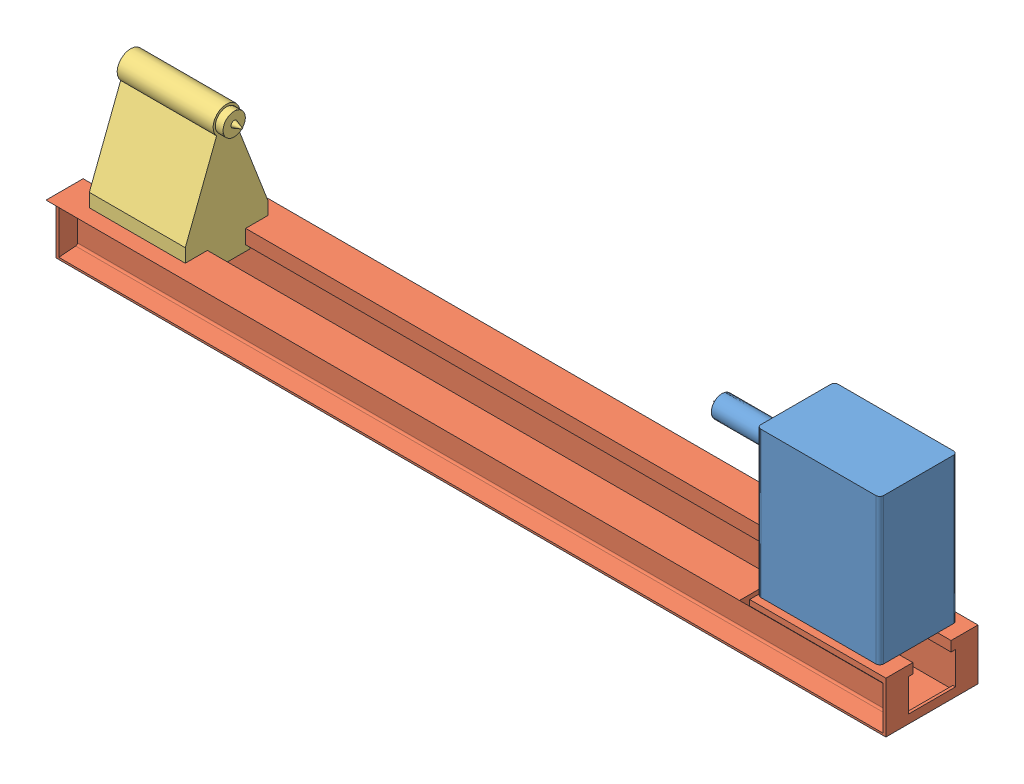
SolidWorks assembly tokarka, configuration Domyślna. Lengths in mm.
Overall size (2162 513 293).
3 component instances, 3 part files, 5 mates.
Components (placement in the parent):
- tokarka-centrala-3: tokarka-centrala [Domyślna] at (-217.5954 -502.6134 690.9735) size (534.85 380 202)
- tokarka-szyna-5: tokarka-szyna [Domyślna] at (-197.0856 -444.2817 671.9735) x (0 0 1) z (-1 0 0) size (293 144 2162)
- tokarka-konik-1: tokarka-konik [Domyślna] at (-1930.2145 -444.2817 911.9735) x (0 0 -1) z (1 0 0) size (215 357.23 292.85)
Mates (geometry in assembly coordinates):
- Wspólnie15: coincident anti-aligned: plane of tokarka-szyna-5 through (-1997.0856 -337.2817 841.7735) normal (0 0 -1); plane of tokarka-konik-1 through (-1680.2145 -444.2817 841.7735) normal (0 0 1)
- Wspólnie16: coincident anti-aligned: plane of tokarka-szyna-5 through (-1997.0856 -300.2817 841.7735) normal (0 1 0); plane of tokarka-konik-1 through (-1680.2145 -300.2817 911.9735) normal (0 -1 0)
- Wspólnie17: coincident anti-aligned: plane of tokarka-centrala-3 through (-197.0856 68.7183 892.9735) normal (-1 0 0); plane of tokarka-szyna-5 through (-197.0856 -444.2817 671.9735) normal (1 0 0)
- Wspólnie18: coincident anti-aligned: plane of tokarka-centrala-3 through (-197.0856 -311.2817 892.9735) normal (0 -1 0); plane of tokarka-szyna-5 through (150.9144 -311.2817 671.9735) normal (0 1 0)
- Odległość1: distance = 19 mm: line of tokarka-centrala-3 through (-187.0856 -311.2817 690.9735) axis (1 0 0); line of tokarka-szyna-5 through (157.9144 -311.2817 671.9735) axis (-1 0 0)
